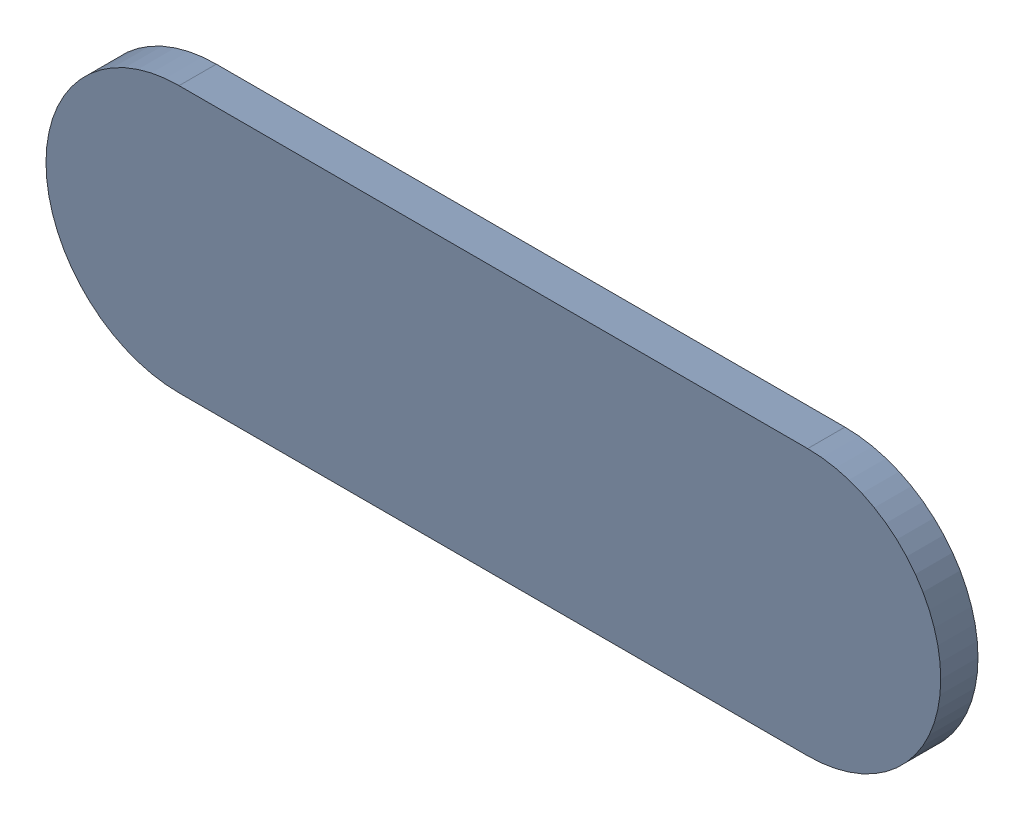
SolidWorks assembly Track (13.9mm,23.75mm)(14.5mm,23.75mm) on Top Layer, configuration Predeterminado. Lengths in mm.
Overall size (0.85 0.25 0.04).
2 component instances, 1 part files, 0 mates.
Components (placement in the parent):
- Track (13.9mm,23.75mm)(14.5mm,23.75mm) on Top Layer-1-1: Track (13.9mm,23.75mm)(14.5mm,23.75mm) on Top Layer-1 [Predeterminado] at (-68.317 -44.187 -0.0457) size (0.85 0.25 0.04)
  - Track (13.9mm,23.75mm)(14.5mm,23.75mm) on Top Layer-Part-1-1: Track (13.9mm,23.75mm)(14.5mm,23.75mm) on Top Layer-Part-1 [Predeterminado] at origin size (0.85 0.25 0.04)
